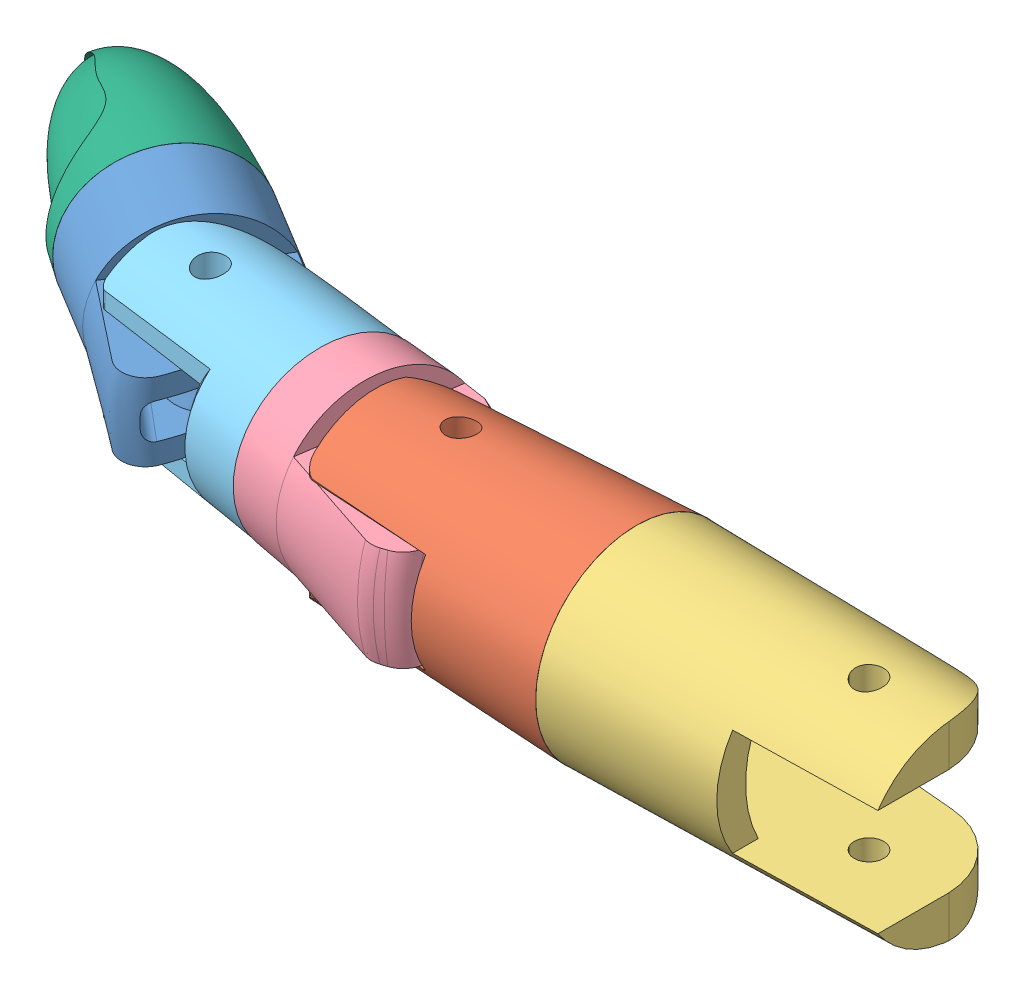
SolidWorks assembly Auriculaire3 montaj, configuration Varsayılan. Lengths in mm.
6 component instances, 6 part files, 15 mates.
Components (placement in the parent):
- Auriculaire3-2-1: Auriculaire3-2 [Varsayılan] at (-12.6239 19.3606 14.3067) x (-0.518778 0 0.854909) z (0.854909 0 0.518778) size (12.29 11.75 15.06)
- Auriculaire3-3-1: Auriculaire3-3 [Varsayılan] at (28.3255 19.3606 22.2384) size (18.34 14.17 14.17)
- Auriculaire3-4-1: Auriculaire3-4 [Varsayılan] at (28.3255 19.3606 22.2384) x (0 -1 0) z (0 0 1) size (14.17 22.51 14.17)
- Auriculaire3-5-1: Auriculaire3-5 [Varsayılan] at (5.6159 19.3606 20.7864) x (0.989471 0 0.14473) z (0 -1 0) size (14.56 13.77 12.85)
- Auriculaire3-6-1: Auriculaire3-6 [Varsayılan] at (-7.5797 19.3606 18.8563) x (0.989471 0 0.14473) z (0.14473 0 -0.989471) size (13.34 12.63 12.44)
- Paramak ucu Auriculaire3-1: Paramak ucu Auriculaire3 [Varsayılan] at (-12.6239 19.3606 14.3067) x (0 1 0) z (-0.518778 0 0.854909) size (11.68 14.17 11.68)
Mates (geometry in assembly coordinates):
- Coincident1: coincident anti-aligned: plane of Auriculaire3-3-1 through (28.3255 19.3606 22.2384) normal (1 0 0); plane of Auriculaire3-4-1 through (28.3255 19.3606 22.2384) normal (-1 0 0)
- Concentric1: concentric anti-aligned: cone of Auriculaire3-3-1 through (9.9885 19.3606 22.2384) axis (-1 0 0); cone of Auriculaire3-4-1 through (28.3255 19.3606 22.2384) axis (1 0 0)
- Coincident4: coincident anti-aligned: plane of Auriculaire3-3-1 through (28.3255 22.903 30.5734) normal (0 -1 0); plane of Auriculaire3-5-1 through (13.8777 22.903 22.8982) normal (0 1 0)
- Concentric3: concentric aligned: cylinder of Auriculaire3-3-1 through (15.5729 27.6956 21.8216) axis (0 -1 0) radius 1.0419; cylinder of Auriculaire3-5-1 through (15.5729 25.7845 21.8216) axis (0 -1 0) radius 1.0419
- Coincident5: coincident anti-aligned: plane of Auriculaire3-5-1 through (5.7143 19.3606 20.0836) normal (-0.976732 0 -0.214463); plane of Auriculaire3-6-1 through (4.3736 -0.0183 26.1894) normal (0.976732 0 0.214463)
- Concentric4: concentric aligned: cone of Auriculaire3-5-1 through (5.7143 19.3606 20.0836) axis (-0.976732 0 -0.214463); cone of Auriculaire3-6-1 through (7.3425 19.3606 20.4411) axis (-0.976732 0 -0.214463)
- Coincident7: coincident anti-aligned: plane of Auriculaire3-2-1; plane of Paramak ucu Auriculaire3-1
- Concentric6: concentric aligned: circle of Auriculaire3-2-1; circle of Paramak ucu Auriculaire3-1
- Coincident9: coincident aligned: plane of Auriculaire3-2-1; plane of Paramak ucu Auriculaire3-1
- Coincident10: coincident anti-aligned: plane of Auriculaire3-5-1; plane of Auriculaire3-6-1 through (-7.3114 19.3606 17.2235) normal (0.214463 0 -0.976732)
- Coincident11: coincident aligned: plane of Auriculaire3-3-1 through (28.3255 19.3606 22.2384) normal (0 0 1); plane of Auriculaire3-4-1 through (28.3255 19.3606 22.2384) normal (0 0 1)
- LimitAngle2: limit planar angle = 2.996352 rad anti-aligned: plane of Auriculaire3-5-1; plane of Auriculaire3-3-1 through (28.3255 19.3606 22.2384) normal (0 0 1)
- Width1: width anti-aligned: plane of Auriculaire3-2-1 through (-12.4824 22.0695 12.7193) normal (0 1 0); plane of Auriculaire3-2-1 through (-12.4824 16.6517 12.7193) normal (0 -1 0); plane of Auriculaire3-6-1 through (-7.3114 22.0695 17.2235) normal (0 -1 0); plane of Auriculaire3-6-1 through (-7.3114 16.6517 17.2235) normal (0 1 0)
- Concentric7: concentric aligned: cylinder of Auriculaire3-2-1 through (-3.4197 25.2368 18.9314) axis (0 -1 0) radius 1.0419; cylinder of Auriculaire3-6-1 through (-3.4197 25.6119 18.9314) axis (0 -1 0) radius 1.0419
- LimitAngle5: limit planar angle = 2.741412 rad aligned: plane of Auriculaire3-2-1; plane of Auriculaire3-6-1 through (-7.5797 19.3606 18.8563) normal (0.14473 0 -0.989471)
